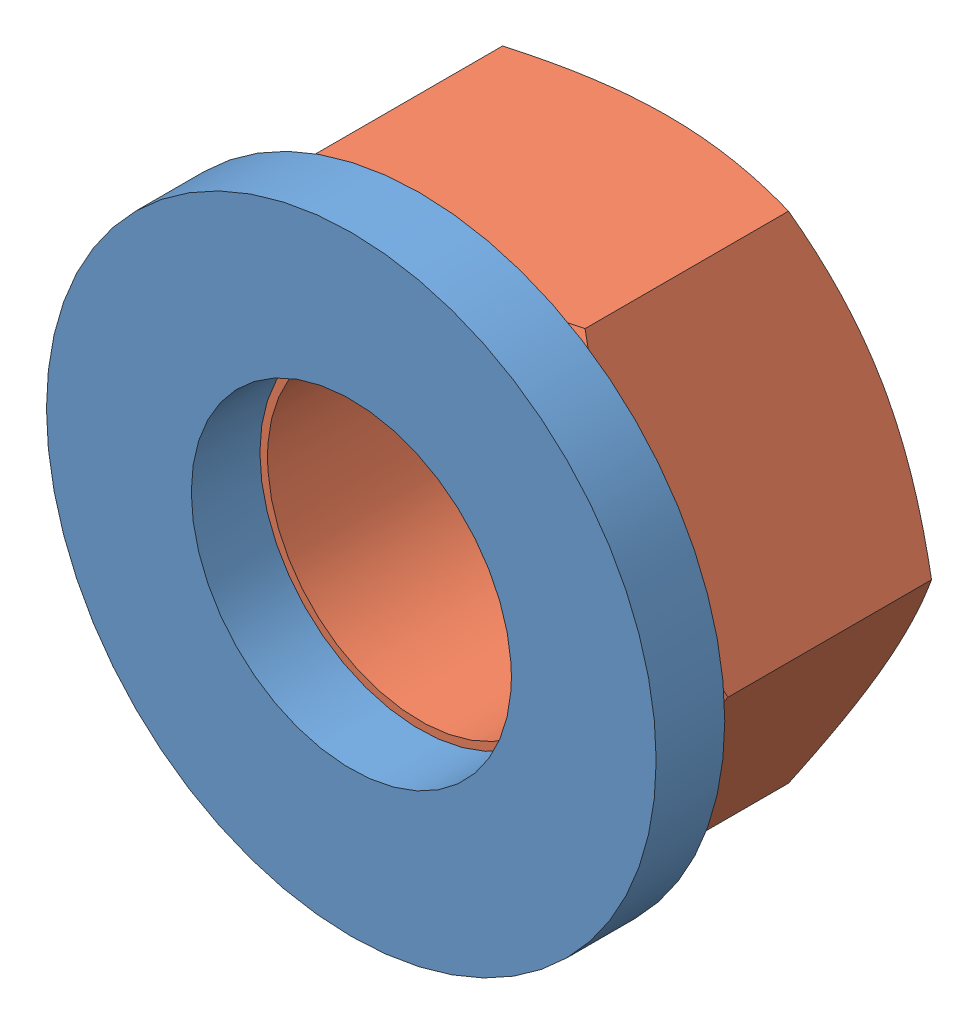
SolidWorks assembly hex nut, flat washer, DIN 125, 934, configuration M08. Lengths in mm.
Overall size (16 16 8.3).
2 component instances, 2 part files, 2 mates.
Components (placement in the parent):
- flat washer, DIN 125-1: flat washer, DIN 125 [M08.0 Zinc Plated Class 4 Steel] x (1 0 0) z (0 0 -1)
- hex nut, DIN 934-1: hex nut, DIN 934 [M08x1.25] at (0 0 -1.8) x (-1 0 0) z (0 0 -1)
Mates (geometry in assembly coordinates):
- Coincident101: coincident anti-aligned: plane of flat washer, DIN 125-1 through (0 0 -1.8) normal (0 0 -1); plane of hex nut, DIN 934-1 through (0 0 -1.8) normal (0 0 1)
- Concentric1: concentric aligned: cylinder of flat washer, DIN 125-1 through (0 0 -1.8) axis (0 0 1) radius 4.2; cylinder of hex nut, DIN 934-1 through (0 0 -8.3) axis (0 0 1) radius 4
